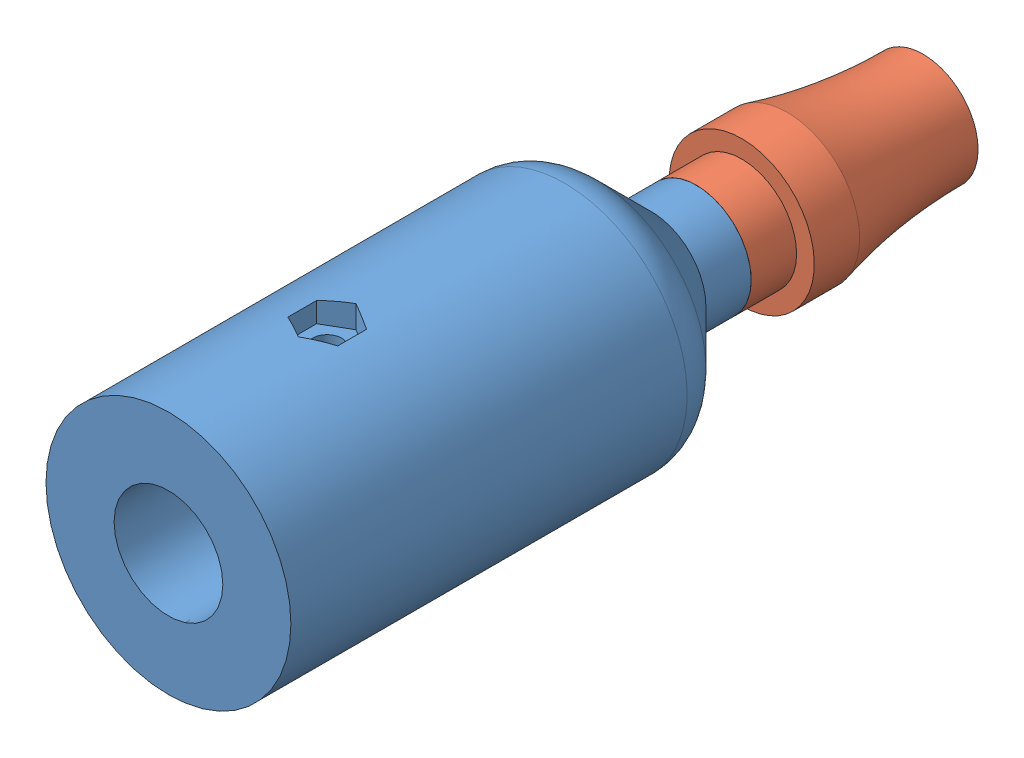
SolidWorks assembly threadedRodEndBearingCoupler, configuration Default. Lengths in mm.
Overall size (27 27 83.2).
2 component instances, 2 part files, 1 mates.
Components (placement in the parent):
- bearingToThreadedRodCouplerLongerV2Part1-1: bearingToThreadedRodCouplerLongerV2Part1 [Default] at (15.2434 29.6272 21.3084) size (27 27 58.2)
- bearingToThreadedRodCouplerLongerV2SecondPart-1: bearingToThreadedRodCouplerLongerV2SecondPart [Default] at (15.2434 29.6272 6.3084) x (0.999764 -0.021722 0) z (0.021722 0.999764 0) size (16 25 16)
Mates (geometry in assembly coordinates):
- Coincident1: coincident anti-aligned: circle of bearingToThreadedRodCouplerLongerV2Part1-1; circle of bearingToThreadedRodCouplerLongerV2SecondPart-1
